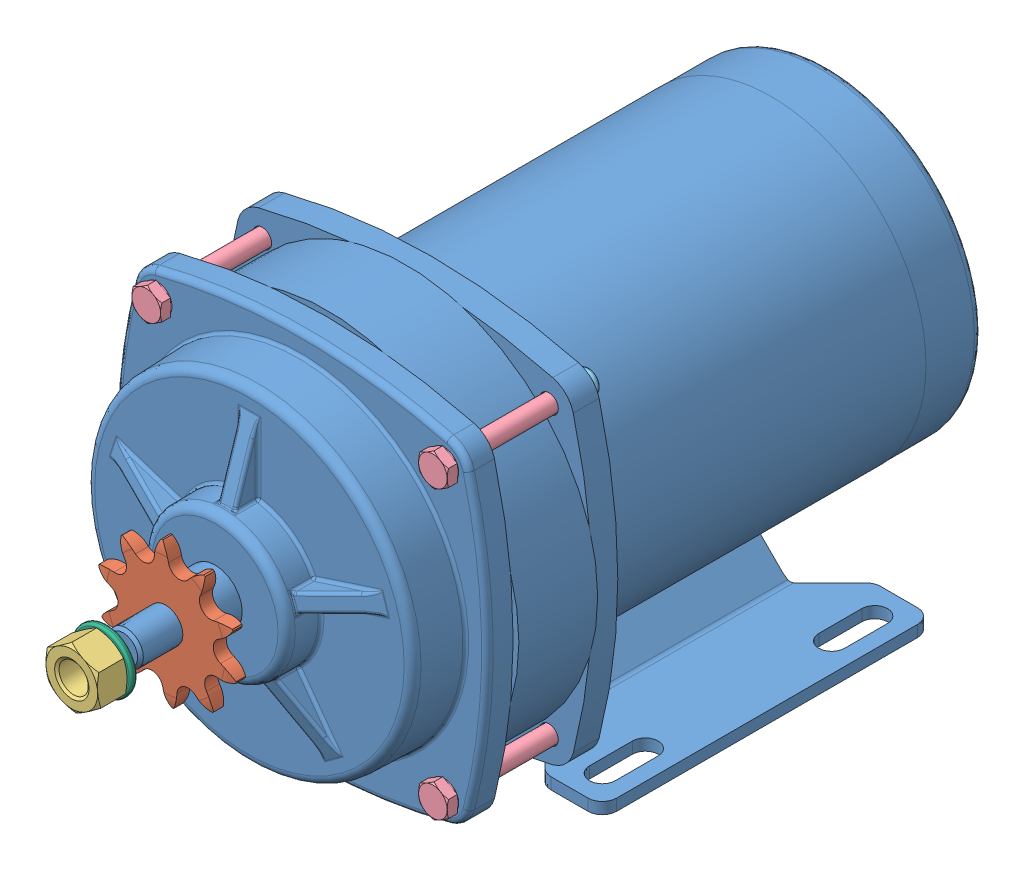
SolidWorks assembly 1020ZXF-36V_500W, configuration Default. Lengths in mm.
Overall size (142 134 263.95).
12 component instances, 6 part files, 5 mates.
Components (placement in the parent):
- 1020ZXF-36V_500W_Motor(Domyœlna_As Machined_)-1: 1020ZXF-36V_500W_Motor(Domyœlna_As Machined_) [Default] at origin size (142 134 246)
- Chain wheel DIN 8192 - A 10Z 083-1: Chain wheel DIN 8192 - A 10Z 083 [Default] at (0 0 83.7384) x (0 0 -1) z (-0.648186 0.761482 0) size (6.02 48.2 49.22)
- ISO 4034 - M12-1: ISO 4034 - M12 [Default] at (0 0 116.4471) x (0.997504 0.070613 0) z (0 0 1) size (18 20.78 10.2)
- ISO 4017 - M6 x 50-1: ISO 4017 - M6 x 50 [Default] at (-50 50 40.5) x (0 0 -1) z (1 0 0) size (54 11.55 10)
- ISO 4017 - M6 x 50-2: ISO 4017 - M6 x 50 [Default] at (50 50 40.5) x (0 0 -1) z (1 0 0) size (54 11.55 10)
- ISO 4017 - M6 x 50-3: ISO 4017 - M6 x 50 [Default] at (50 -50 40.5) x (0 0 -1) z (1 0 0) size (54 11.55 10)
- ISO 4017 - M6 x 50-4: ISO 4017 - M6 x 50 [Default] at (-50 -50 40.5) x (0 0 -1) z (1 0 0) size (54 11.55 10)
- ISO 10511-M5-1: ISO 10511-M5 [Default] at (50 50 -11.45) x (0.923728 0.383049 0) z (0 0 -1) size (8 9.24 5)
- ISO 10511-M5-2: ISO 10511-M5 [Default] at (-50 50 -11.45) x (0.923728 0.383049 0) z (0 0 -1) size (8 9.24 5)
- ISO 10511-M5-3: ISO 10511-M5 [Default] at (-50 -50 -11.45) x (0.923728 0.383049 0) z (0 0 -1) size (8 9.24 5)
- ISO 10511-M5-4: ISO 10511-M5 [Default] at (50 -50 -11.45) x (0.923728 0.383049 0) z (0 0 -1) size (8 9.24 5)
- DIN 128 - A12-1: DIN 128 - A12 [Default] at (0 0 106.2471) x (0 0 1) z (-1 0 0) size (2.21 21.1 21.13)
Mates (geometry in assembly coordinates):
- Concentric1: concentric anti-aligned: cylinder of 1020ZXF-36V_500W_Motor(Domyœlna_As Machined_)-1 through (0 0 98.5) axis (0 0 -1) radius 6; cylinder of Chain wheel DIN 8192 - A 10Z 083-1 through (0 0 33.7379) axis (0 0 1) radius 6
- Coincident1: coincident anti-aligned: plane of 1020ZXF-36V_500W_Motor(Domyœlna_As Machined_)-1 through (0 0 79.2) normal (0 0 1); plane of Chain wheel DIN 8192 - A 10Z 083-1 through (0 0 79.2) normal (0 0 -1)
- Concentric2: concentric anti-aligned: cylinder of ISO 4034 - M12-1 through (0 0 106.2471) axis (0 0 1) radius 5.1; circle of DIN 128 - A12-1
- Coincident2: coincident anti-aligned: plane of ISO 4034 - M12-1 through (-17.9551 -1.271 106.2471) normal (0 0 -1); plane of DIN 128 - A12-1 through (0 7.1 106.2471) normal (0 0 1)
- Concentric3: concentric anti-aligned: cylinder of 1020ZXF-36V_500W_Motor(Domyœlna_As Machined_)-1 through (0 0 98.5) axis (0 0 -1) radius 6; cylinder of ISO 4034 - M12-1 through (0 0 106.2471) axis (0 0 1) radius 5.1
